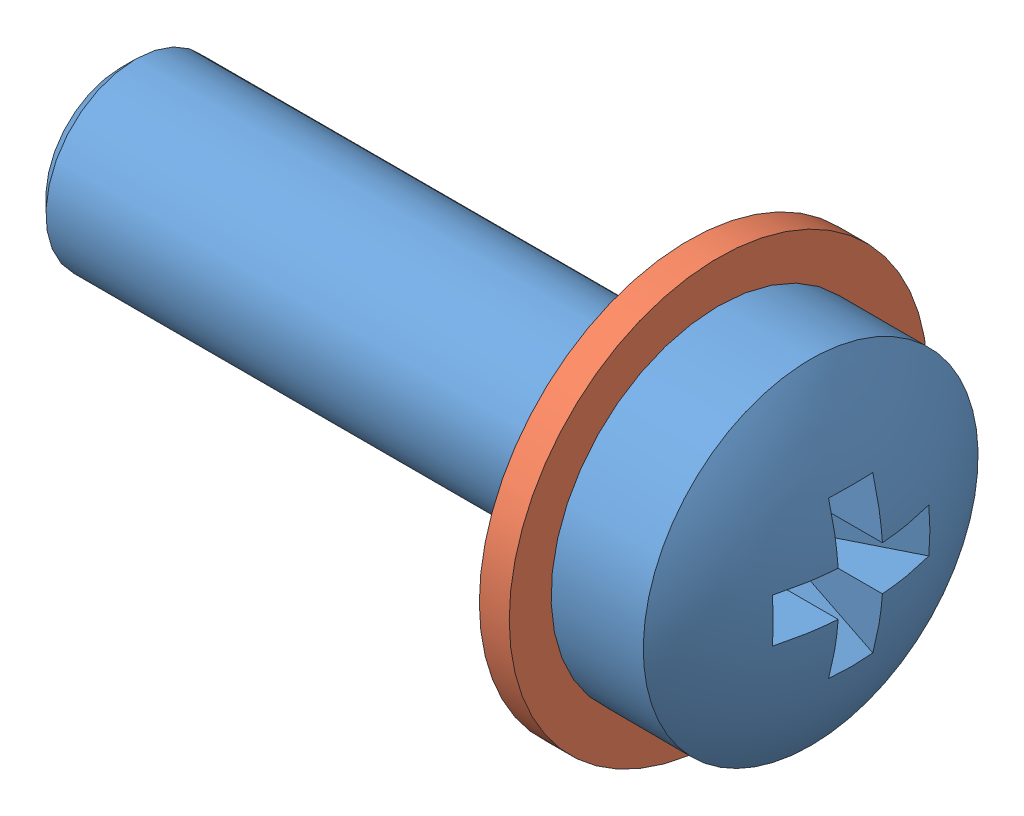
SolidWorks assembly Assembly Screw DIN 7985 - M3 x 10 --- 10N + Washer DIN 125A - M3, configuration Valor predeterminado. Lengths in mm.
Overall size (12.37 7 7).
2 component instances, 2 part files, 2 mates.
Components (placement in the parent):
- Screw DIN 7985 - M3 x 10 --- 10N-1: Screw DIN 7985 - M3 x 10 --- 10N [Valor predeterminado] at (5.7786 -0.3419 12.3725) size (12.37 5.6 5.6)
- Washer DIN 125A - M3-1: Washer DIN 125A - M3 [Valor predeterminado] at (2.8786 -0.3419 12.3725) size (0.5 7 7)
Mates (geometry in assembly coordinates):
- Concêntrico1: concentric: cylinder of assembly; cylinder of assembly; cylinder of Screw DIN 7985 - M3 x 10 --- 10N-1 through (5.7786 -0.3419 12.3725) axis (1 0 0) radius 1.5; cylinder of Washer DIN 125A - M3-1 through (3.3786 -0.3419 12.3725) axis (-1 0 0) radius 1.6
- Coincidente1: coincident: plane of assembly; plane of assembly; plane of Screw DIN 7985 - M3 x 10 --- 10N-1 through (3.3786 1.1581 12.3725) normal (-1 0 0); plane of Washer DIN 125A - M3-1 through (3.3786 -0.3419 12.3725) normal (1 0 0)
